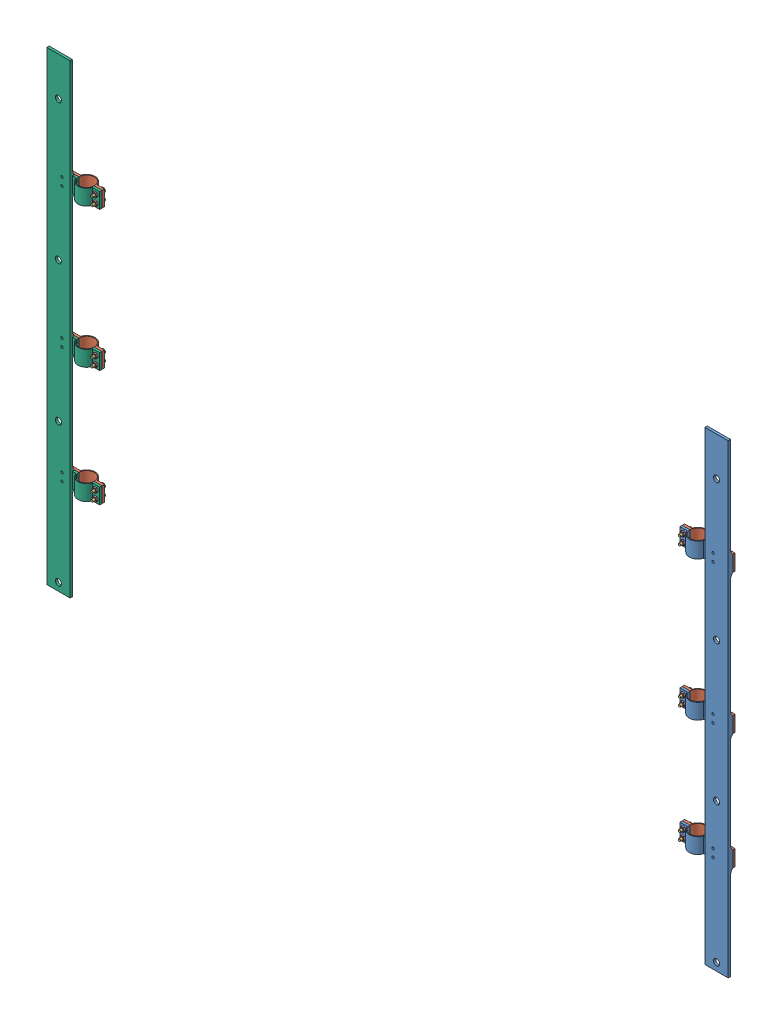
SolidWorks assembly 连接, configuration 默认. Lengths in mm.
Overall size (878.7 600 22).
45 component instances, 6 part files, 47 mates.
Components (placement in the parent):
- 剪叉-框连接-1: 剪叉-框连接 [默认] at (13.2887 -9.5519 -2.5) size (65.2 600 11)
- 框连接夹具-1: 框连接夹具 [默认] at (-31.9113 160.4415 -5.5) x (0 0 1) z (0 -1 0) size (11 65.2 20)
- 框连接夹具-2: 框连接夹具 [默认] at (-31.9113 -19.5585 -5.5) x (0 0 1) z (0 -1 0) size (11 65.2 20)
- 框连接夹具-3: 框连接夹具 [默认] at (-31.9113 -169.5585 -5.5) x (0 0 1) z (0 -1 0) size (11 65.2 20)
- hexagon socket head cap screws gb-4: hexagon socket head cap screws gb [GB_FASTENER_SCREWS_HSHCS M3X12-N] at (-47.2028 -184.5585 -12) x (0 0 1) z (-1 0 0) size (15 5.5 5.5)
- hex nuts, style 1-grades ab gb-8: hex nuts, style 1-grades ab gb [GB_FASTENER_NUT_SNAB1 M3-N] at (-47.2028 -174.5585 -0.1) size (6.35 5.5 2.4)
- hexagon socket head cap screws gb-11: hexagon socket head cap screws gb [GB_FASTENER_SCREWS_HSHCS M3X12-N] at (-47.2028 -34.5585 -12) x (0 0 1) z (-1 0 0) size (15 5.5 5.5)
- plain washers-n series-grade a gb-6: plain washers-n series-grade a gb [GB_FASTENER_WASHER_PWNA 3] at (-47.2028 -184.5585 -9) x (0.923728 0.383049 0) z (0 0 -1) size (7 7 0.5)
- hexagon socket head cap screws gb-3: hexagon socket head cap screws gb [GB_FASTENER_SCREWS_HSHCS M3X12-N] at (-47.2028 -174.5585 -12) x (0 0 1) z (-1 0 0) size (15 5.5 5.5)
- hexagon socket head cap screws gb-6: hexagon socket head cap screws gb [GB_FASTENER_SCREWS_HSHCS M3X12-N] at (-47.2028 -24.5585 -12) x (0 0 1) z (-1 0 0) size (15 5.5 5.5)
- hexagon socket head cap screws gb-7: hexagon socket head cap screws gb [GB_FASTENER_SCREWS_HSHCS M3X12-N] at (-47.2028 155.4415 -12) x (0 0 1) z (-1 0 0) size (15 5.5 5.5)
- hexagon socket head cap screws gb-8: hexagon socket head cap screws gb [GB_FASTENER_SCREWS_HSHCS M3X12-N] at (-47.2028 145.4415 -12) x (0 0 1) z (-1 0 0) size (15 5.5 5.5)
- hex nuts, style 1-grades ab gb-2: hex nuts, style 1-grades ab gb [GB_FASTENER_NUT_SNAB1 M3-N] at (-47.2028 155.4415 -0.1) size (6.35 5.5 2.4)
- hex nuts, style 1-grades ab gb-4: hex nuts, style 1-grades ab gb [GB_FASTENER_NUT_SNAB1 M3-N] at (-47.2028 145.4415 -0.1) size (6.35 5.5 2.4)
- hex nuts, style 1-grades ab gb-5: hex nuts, style 1-grades ab gb [GB_FASTENER_NUT_SNAB1 M3-N] at (-47.2028 -24.5585 -0.1) size (6.35 5.5 2.4)
- hex nuts, style 1-grades ab gb-6: hex nuts, style 1-grades ab gb [GB_FASTENER_NUT_SNAB1 M3-N] at (-47.2028 -34.5585 -0.1) size (6.35 5.5 2.4)
- hex nuts, style 1-grades ab gb-7: hex nuts, style 1-grades ab gb [GB_FASTENER_NUT_SNAB1 M3-N] at (-47.2028 -184.5585 -0.1) size (6.35 5.5 2.4)
- hexagon socket head cap screws gb-9: hexagon socket head cap screws gb [GB_FASTENER_SCREWS_HSHCS M3X12-N] at (-47.2028 -34.5585 -12) x (0 0 1) z (-1 0 0) size (15 5.5 5.5)
- plain washers-n series-grade a gb-10: plain washers-n series-grade a gb [GB_FASTENER_WASHER_PWNA 3] at (-47.2028 -34.5585 -9) x (0.923728 0.383049 0) z (0 0 -1) size (7 7 0.5)
- plain washers-n series-grade a gb-12: plain washers-n series-grade a gb [GB_FASTENER_WASHER_PWNA 3] at (-47.2028 -174.5585 -9) x (0.923728 0.383049 0) z (0 0 -1) size (7 7 0.5)
- plain washers-n series-grade a gb-13: plain washers-n series-grade a gb [GB_FASTENER_WASHER_PWNA 3] at (-47.2028 -24.5585 -9) x (0.923728 0.383049 0) z (0 0 -1) size (7 7 0.5)
- plain washers-n series-grade a gb-15: plain washers-n series-grade a gb [GB_FASTENER_WASHER_PWNA 3] at (-47.2028 155.4415 -9) x (0.923728 0.383049 0) z (0 0 -1) size (7 7 0.5)
- 剪叉-框连接 - 副本-1: 剪叉-框连接 - 副本 [默认] at (-835.4113 -9.5519 -2.5) size (65.2 600 11)
- 框连接夹具-4: 框连接夹具 [默认] at (-820.2113 140.4415 -5.5) x (0 0 1) z (0 1 0) size (11 65.2 20)
- 框连接夹具-5: 框连接夹具 [默认] at (-820.2113 -39.5585 -5.5) x (0 0 1) z (0 1 0) size (11 65.2 20)
- 框连接夹具-6: 框连接夹具 [默认] at (-820.2113 -189.5585 -5.5) x (0 0 1) z (0 1 0) size (11 65.2 20)
- hexagon socket head cap screws gb-13: hexagon socket head cap screws gb [GB_FASTENER_SCREWS_HSHCS M3X12-N] at (-804.9198 -184.5585 -12) x (0 0 1) z (-1 0 0) size (15 5.5 5.5)
- hex nuts, style 1-grades ab gb-10: hex nuts, style 1-grades ab gb [GB_FASTENER_NUT_SNAB1 M3-N] at (-804.9198 -174.5585 -2.5) x (-1 0 0) z (0 0 -1) size (6.35 5.5 2.4)
- hexagon socket head cap screws gb-14: hexagon socket head cap screws gb [GB_FASTENER_SCREWS_HSHCS M3X12-N] at (-804.9198 -34.5585 -12) x (0 0 1) z (-1 0 0) size (15 5.5 5.5)
- plain washers-n series-grade a gb-16: plain washers-n series-grade a gb [GB_FASTENER_WASHER_PWNA 3] at (-804.9198 -184.5585 -8.5) x (-0.923728 0.383049 0) z (0 0 1) size (7 7 0.5)
- hexagon socket head cap screws gb-15: hexagon socket head cap screws gb [GB_FASTENER_SCREWS_HSHCS M3X12-N] at (-804.9198 -174.5585 -12) x (0 0 1) z (-1 0 0) size (15 5.5 5.5)
- hexagon socket head cap screws gb-16: hexagon socket head cap screws gb [GB_FASTENER_SCREWS_HSHCS M3X12-N] at (-804.9198 -24.5585 -12) x (0 0 1) z (-1 0 0) size (15 5.5 5.5)
- hexagon socket head cap screws gb-17: hexagon socket head cap screws gb [GB_FASTENER_SCREWS_HSHCS M3X12-N] at (-804.9198 155.4415 -12) x (0 0 1) z (-1 0 0) size (15 5.5 5.5)
- hexagon socket head cap screws gb-18: hexagon socket head cap screws gb [GB_FASTENER_SCREWS_HSHCS M3X12-N] at (-804.9198 145.4415 -12) x (0 0 1) z (-1 0 0) size (15 5.5 5.5)
- hex nuts, style 1-grades ab gb-11: hex nuts, style 1-grades ab gb [GB_FASTENER_NUT_SNAB1 M3-N] at (-804.9198 155.4415 -2.5) x (-1 0 0) z (0 0 -1) size (6.35 5.5 2.4)
- hex nuts, style 1-grades ab gb-12: hex nuts, style 1-grades ab gb [GB_FASTENER_NUT_SNAB1 M3-N] at (-804.9198 145.4415 -2.5) x (-1 0 0) z (0 0 -1) size (6.35 5.5 2.4)
- hex nuts, style 1-grades ab gb-13: hex nuts, style 1-grades ab gb [GB_FASTENER_NUT_SNAB1 M3-N] at (-804.9198 -24.5585 -2.5) x (-1 0 0) z (0 0 -1) size (6.35 5.5 2.4)
- hex nuts, style 1-grades ab gb-14: hex nuts, style 1-grades ab gb [GB_FASTENER_NUT_SNAB1 M3-N] at (-804.9198 -34.5585 -2.5) x (-1 0 0) z (0 0 -1) size (6.35 5.5 2.4)
- hex nuts, style 1-grades ab gb-15: hex nuts, style 1-grades ab gb [GB_FASTENER_NUT_SNAB1 M3-N] at (-804.9198 -184.5585 -2.5) x (-1 0 0) z (0 0 -1) size (6.35 5.5 2.4)
- hexagon socket head cap screws gb-19: hexagon socket head cap screws gb [GB_FASTENER_SCREWS_HSHCS M3X12-N] at (-804.9198 -34.5585 -12) x (0 0 1) z (-1 0 0) size (15 5.5 5.5)
- plain washers-n series-grade a gb-17: plain washers-n series-grade a gb [GB_FASTENER_WASHER_PWNA 3] at (-804.9198 -34.5585 -8.5) x (-0.923728 0.383049 0) z (0 0 1) size (7 7 0.5)
- plain washers-n series-grade a gb-18: plain washers-n series-grade a gb [GB_FASTENER_WASHER_PWNA 3] at (-804.9198 -174.5585 -8.5) x (-0.923728 0.383049 0) z (0 0 1) size (7 7 0.5)
- plain washers-n series-grade a gb-19: plain washers-n series-grade a gb [GB_FASTENER_WASHER_PWNA 3] at (-804.9198 -24.5585 -8.5) x (-0.923728 0.383049 0) z (0 0 1) size (7 7 0.5)
- plain washers-n series-grade a gb-20: plain washers-n series-grade a gb [GB_FASTENER_WASHER_PWNA 3] at (-804.9198 155.4415 -8.5) x (-0.923728 0.383049 0) z (0 0 1) size (7 7 0.5)
- plain washers-n series-grade a gb-21: plain washers-n series-grade a gb [GB_FASTENER_WASHER_PWNA 3] at (-47.2028 145.4415 -8.5) x (-0.923728 0.383049 0) z (0 0 1) size (7 7 0.5)
Mates (geometry in assembly coordinates):
- 同心1: concentric anti-aligned: cylinder of 剪叉-框连接-1 through (-31.9113 160.4415 -5.5) axis (0 -1 0) radius 10; cylinder of 框连接夹具-1 through (-31.9113 140.4415 -5.5) axis (0 1 0) radius 10
- 同心2: concentric anti-aligned: cylinder of 剪叉-框连接-1 through (-6.2113 145.4415 -19.5) axis (0 0 1) radius 1.5; circle of 框连接夹具-1
- 同心3: concentric anti-aligned: cylinder of 剪叉-框连接-1 through (-31.9113 -19.5585 -5.5) axis (0 -1 0) radius 10; cylinder of 框连接夹具-2 through (-31.9113 -39.5585 -5.5) axis (0 1 0) radius 10
- 同心4: concentric anti-aligned: cylinder of 剪叉-框连接-1 through (-6.2113 -34.5585 -19.5) axis (0 0 1) radius 1.5; cylinder of 框连接夹具-2 through (-6.2113 -34.5585 11.5) axis (0 0 -1) radius 1.5
- 同心5: concentric anti-aligned: cylinder of 剪叉-框连接-1 through (-31.9113 -169.5585 -5.5) axis (0 -1 0) radius 10; cylinder of 框连接夹具-3 through (-31.9113 -189.5585 -5.5) axis (0 1 0) radius 10
- 同心6: concentric anti-aligned: cylinder of 剪叉-框连接-1 through (-6.2113 -184.5585 -19.5) axis (0 0 1) radius 1.5; cylinder of 框连接夹具-3 through (-6.2113 -184.5585 11.5) axis (0 0 -1) radius 1.5
- 同心11: concentric aligned: cylinder of 框连接夹具-3 through (-47.2028 -184.5585 11.5) axis (0 0 -1) radius 1.5; cylinder of plain washers-n series-grade a gb-6 through (-47.2028 -184.5585 -8.5) axis (0 0 -1) radius 1.6
- 重合7: coincident anti-aligned: plane of 框连接夹具-3 through (-31.9113 -189.5585 -8.5) normal (0 0 -1); plane of plain washers-n series-grade a gb-6 through (-47.2028 -184.5585 -8.5) normal (0 0 1)
- 同心14: concentric aligned: cylinder of 框连接夹具-3 through (-47.2028 -184.5585 11.5) axis (0 0 -1) radius 1.5; cylinder of hexagon socket head cap screws gb-4 through (-47.2028 -184.5585 3) axis (0 0 -1) radius 1.5
- 重合10: coincident anti-aligned: plane of plain washers-n series-grade a gb-6 through (-47.2028 -184.5585 -9) normal (0 0 -1); plane of hexagon socket head cap screws gb-4 through (-47.2028 -184.5585 -9) normal (0 0 1)
- 同心16: concentric aligned: cylinder of 框连接夹具-2 through (-47.2028 -24.5585 11.5) axis (0 0 -1) radius 1.5; cylinder of hexagon socket head cap screws gb-6 through (-47.2028 -24.5585 3) axis (0 0 -1) radius 1.5
- 同心17: concentric aligned: cylinder of 框连接夹具-1 through (-47.2028 155.4415 11.5) axis (0 0 -1) radius 1.5; cylinder of hexagon socket head cap screws gb-7 through (-47.2028 155.4415 3) axis (0 0 -1) radius 1.5
- 同心18: concentric aligned: cylinder of 框连接夹具-1 through (-47.2028 145.4415 11.5) axis (0 0 -1) radius 1.5; cylinder of hexagon socket head cap screws gb-8 through (-47.2028 145.4415 3) axis (0 0 -1) radius 1.5
- 同心19: concentric anti-aligned: cylinder of hexagon socket head cap screws gb-7 through (-47.2028 155.4415 3) axis (0 0 -1) radius 1.5; cone of hex nuts, style 1-grades ab gb-2 through (-47.2028 155.4415 -2.5) axis (0 0 1)
- 重合15: coincident anti-aligned: plane of 剪叉-框连接-1 through (-51.9113 160.4415 -2.5) normal (0 0 1); plane of hex nuts, style 1-grades ab gb-2 through (-47.2028 149.9415 -2.5) normal (0 0 -1)
- 同心20: concentric anti-aligned: cylinder of hexagon socket head cap screws gb-8 through (-47.2028 145.4415 3) axis (0 0 -1) radius 1.5; cone of hex nuts, style 1-grades ab gb-4 through (-47.2028 145.4415 -2.5) axis (0 0 1)
- 重合17: coincident anti-aligned: plane of 剪叉-框连接-1 through (-51.9113 160.4415 -2.5) normal (0 0 1); plane of hex nuts, style 1-grades ab gb-4 through (-47.2028 139.9415 -2.5) normal (0 0 -1)
- 同心21: concentric anti-aligned: cylinder of hexagon socket head cap screws gb-6 through (-47.2028 -24.5585 3) axis (0 0 -1) radius 1.5; cone of hex nuts, style 1-grades ab gb-5 through (-47.2028 -24.5585 -2.5) axis (0 0 1)
- 重合18: coincident anti-aligned: plane of 剪叉-框连接-1 through (-51.9113 -19.5585 -2.5) normal (0 0 1); plane of hex nuts, style 1-grades ab gb-5 through (-47.2028 -30.0585 -2.5) normal (0 0 -1)
- 重合19: coincident anti-aligned: plane of 剪叉-框连接-1 through (-51.9113 -19.5585 -2.5) normal (0 0 1); plane of hex nuts, style 1-grades ab gb-6 through (-47.2028 -40.0585 -2.5) normal (0 0 -1)
- 同心23: concentric anti-aligned: cylinder of hexagon socket head cap screws gb-4 through (-47.2028 -184.5585 3) axis (0 0 -1) radius 1.5; cone of hex nuts, style 1-grades ab gb-7 through (-47.2028 -184.5585 -2.5) axis (0 0 1)
- 重合20: coincident anti-aligned: plane of 剪叉-框连接-1 through (-51.9113 -169.5585 -2.5) normal (0 0 1); plane of hex nuts, style 1-grades ab gb-7 through (-47.2028 -190.0585 -2.5) normal (0 0 -1)
- 同心24: concentric aligned: cylinder of 剪叉-框连接-1 through (-47.2028 -174.5585 -19.5) axis (0 0 1) radius 1.5; cone of hex nuts, style 1-grades ab gb-8 through (-47.2028 -174.5585 -2.5) axis (0 0 1)
- 重合21: coincident anti-aligned: plane of 剪叉-框连接-1 through (-51.9113 -169.5585 -2.5) normal (0 0 1); plane of hex nuts, style 1-grades ab gb-8 through (-47.2028 -180.0585 -2.5) normal (0 0 -1)
- 重合22: coincident anti-aligned: plane of hexagon socket head cap screws gb-9 through (-47.2028 -34.5585 -9) normal (0 0 1); plane of plain washers-n series-grade a gb-10 through (-47.2028 -34.5585 -9) normal (0 0 -1)
- 重合24: coincident aligned: plane of 剪叉-框连接-1 through (13.2887 -9.5519 -2.5) normal (0 0 -1); plane of 剪叉-框连接 - 副本-1 through (-835.4113 -9.5519 -2.5) normal (0 0 -1)
- 距离1: distance = 439.35 mm anti-aligned: plane of 剪叉-框连接 - 副本-1 through (-865.4113 -9.5519 0.5) normal (-1 0 0); plane of assembly through (-426.0613 0 0) normal (1 0 0)
- 重合26: coincident aligned: plane of 剪叉-框连接-1 through (13.2887 290.4481 0.5) normal (0 1 0); plane of 剪叉-框连接 - 副本-1 through (-835.4113 290.4481 0.5) normal (0 1 0)
- 同心25: concentric aligned: cylinder of 剪叉-框连接 - 副本-1 through (-820.2113 -169.5585 -5.5) axis (0 -1 0) radius 10; cylinder of 框连接夹具-6 through (-820.2113 -169.5585 -5.5) axis (0 -1 0) radius 10
- 重合27: coincident anti-aligned: plane of 剪叉-框连接 - 副本-1 through (-810.2113 -169.5585 -5.5) normal (0 0 -1); plane of 框连接夹具-6 through (-820.2113 -169.5585 -5.5) normal (0 0 1)
- 重合28: coincident aligned: plane of 剪叉-框连接 - 副本-1 through (-820.2113 -169.5585 -5.5) normal (0 1 0); plane of 框连接夹具-6 through (-820.2113 -169.5585 -5.5) normal (0 1 0)
- 同心27: concentric aligned: cylinder of 剪叉-框连接 - 副本-1 through (-820.2113 -19.5585 -5.5) axis (0 -1 0) radius 10; cylinder of 框连接夹具-5 through (-820.2113 -19.5585 -5.5) axis (0 -1 0) radius 10
- 同心36: concentric anti-aligned: cylinder of 剪叉-框连接 - 副本-1 through (-845.9113 -34.5585 -19.5) axis (0 0 1) radius 1.5; cylinder of 框连接夹具-5 through (-845.9113 -34.5585 11.5) axis (0 0 -1) radius 1.5
- 重合29: coincident aligned: plane of 剪叉-框连接 - 副本-1 through (-820.2113 -19.5585 -5.5) normal (0 1 0); plane of 框连接夹具-5 through (-820.2113 -19.5585 -5.5) normal (0 1 0)
- 同心29: concentric aligned: cylinder of 剪叉-框连接 - 副本-1 through (-820.2113 160.4415 -5.5) axis (0 -1 0) radius 10; cylinder of 框连接夹具-4 through (-820.2113 160.4415 -5.5) axis (0 -1 0) radius 10
- 平行4: parallel anti-aligned: cylinder of 剪叉-框连接 - 副本-1 through (-845.9113 145.4415 -19.5) axis (0 0 1) radius 1.5; cylinder of 框连接夹具-4 through (-845.9113 145.4415 11.5) axis (0 0 -1) radius 1.5
- 重合30: coincident aligned: plane of 剪叉-框连接 - 副本-1 through (-820.2113 160.4415 -5.5) normal (0 1 0); plane of 框连接夹具-4 through (-820.2113 160.4415 -5.5) normal (0 1 0)
- 同心30: concentric aligned: cylinder of hexagon socket head cap screws gb-7 through (-47.2028 155.4415 3) axis (0 0 -1) radius 1.5; cylinder of plain washers-n series-grade a gb-15 through (-47.2028 155.4415 -8.5) axis (0 0 -1) radius 1.6
- 同心31: concentric aligned: cylinder of hexagon socket head cap screws gb-6 through (-47.2028 -24.5585 3) axis (0 0 -1) radius 1.5; cylinder of plain washers-n series-grade a gb-13 through (-47.2028 -24.5585 -8.5) axis (0 0 -1) radius 1.6
- 同心32: concentric aligned: cylinder of hexagon socket head cap screws gb-11 through (-47.2028 -34.5585 3) axis (0 0 -1) radius 1.5; cylinder of hexagon socket head cap screws gb-9 through (-47.2028 -34.5585 3) axis (0 0 -1) radius 1.5
- 同心33: concentric aligned: cylinder of 框连接夹具-2 through (-47.2028 -34.5585 11.5) axis (0 0 -1) radius 1.5; cylinder of hexagon socket head cap screws gb-11 through (-47.2028 -34.5585 3) axis (0 0 -1) radius 1.5
- 同心34: concentric aligned: circle of 框连接夹具-2; cylinder of plain washers-n series-grade a gb-10 through (-47.2028 -34.5585 -8.5) axis (0 0 -1) radius 1.6
- 同心35: concentric anti-aligned: cylinder of hexagon socket head cap screws gb-11 through (-47.2028 -34.5585 3) axis (0 0 -1) radius 1.5; cylinder of hex nuts, style 1-grades ab gb-6 through (-47.2028 -34.5585 -2.5) axis (0 0 1) radius 1.2295
- 同心37: concentric aligned: cylinder of 框连接夹具-6 through (-804.9198 -174.5585 11.5) axis (0 0 -1) radius 1.5; cylinder of hexagon socket head cap screws gb-15 through (-804.9198 -174.5585 3) axis (0 0 -1) radius 1.5
- 同心38: concentric anti-aligned: circle of 框连接夹具-6; circle of plain washers-n series-grade a gb-18
- 重合32: coincident anti-aligned: plane of 框连接夹具-1 through (-31.9113 140.4415 -8.5) normal (0 0 -1); plane of plain washers-n series-grade a gb-21 through (-47.2028 145.4415 -8.5) normal (0 0 1)
- 同心40: concentric anti-aligned: cylinder of hexagon socket head cap screws gb-8 through (-47.2028 145.4415 3) axis (0 0 -1) radius 1.5; cylinder of plain washers-n series-grade a gb-21 through (-47.2028 145.4415 -9) axis (0 0 1) radius 1.6
